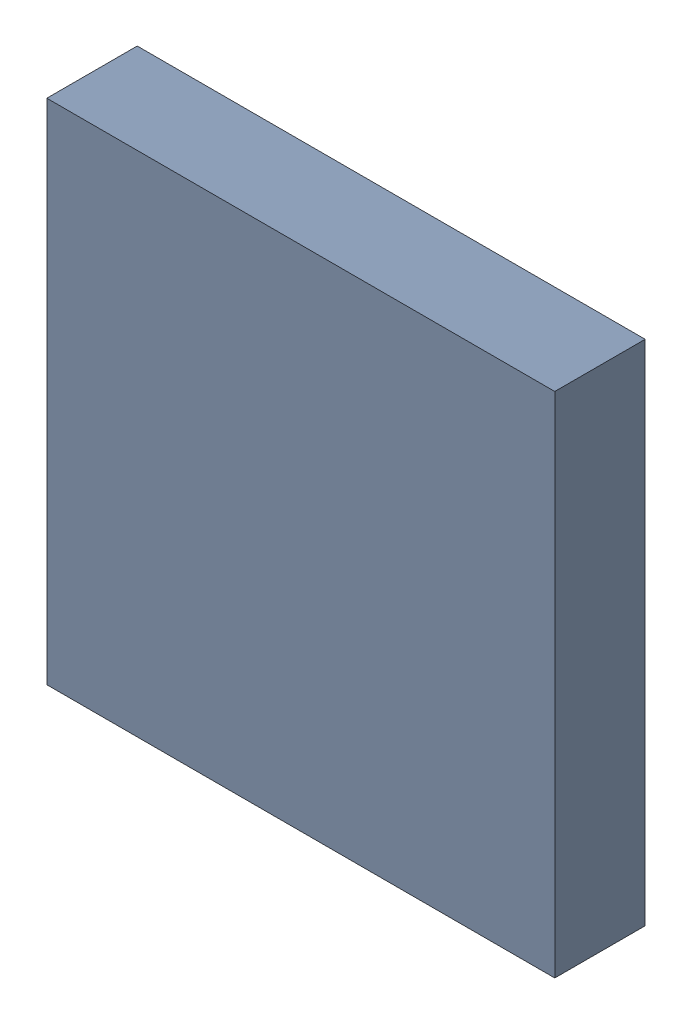
SolidWorks assembly U3, configuration Default. Lengths in mm.
Overall size (5 5 0.89).
2 component instances, 1 part files, 0 mates.
Components (placement in the parent):
- 804367824_1-1: 804367824_1 [Default] at (39.096 35.5884 -1.3115) size (5 5 0.89)
  - Extruded (5)-1: Extruded (5) [Default] at origin size (5 5 0.89)
